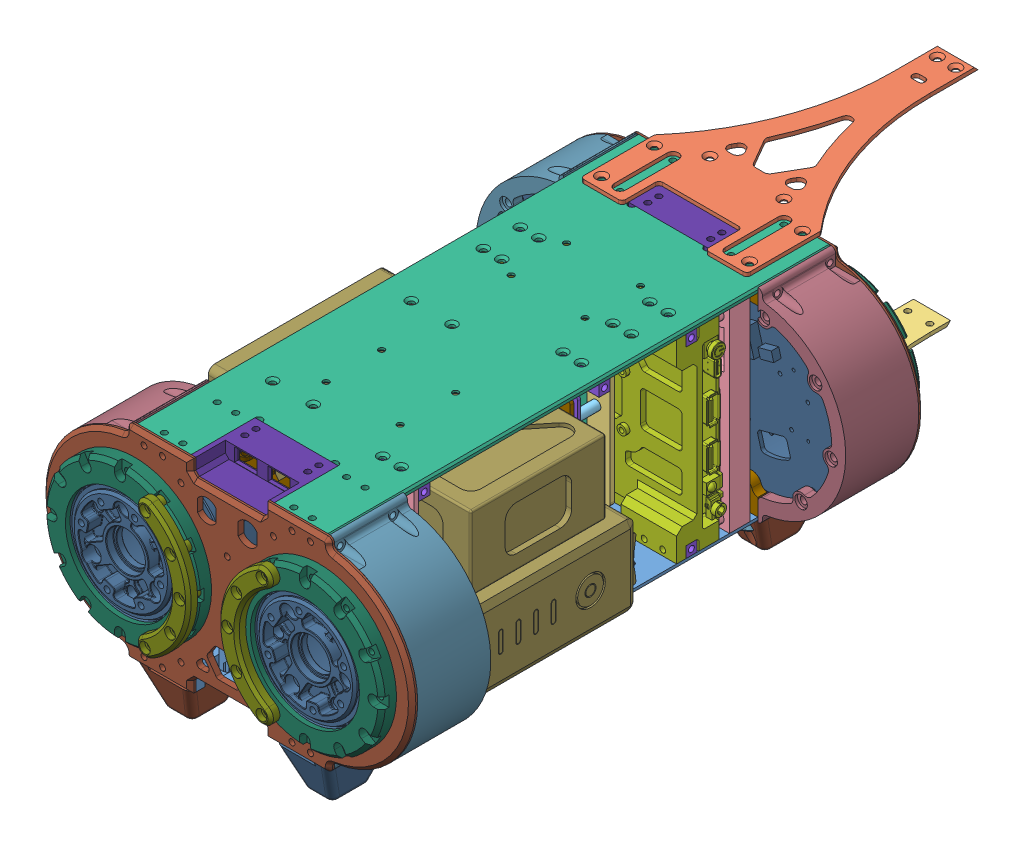
SolidWorks assembly body, configuration 默认. Lengths in mm.
Overall size (225.69 141.84 409).
75 component instances, 29 part files, 207 mates.
Components (placement in the parent):
- 底部碳板-1: 底部碳板 [默认] at (-41.4963 15.0919 267.4422) size (105 2.5 271)
- RoboMaster 电池架-1: RoboMaster 电池架 [默认] at (-3.9963 45.2919 348.8922) x (0 0 -1) z (0 -1 0) size (103.5 37.5 55.4)
- 电池盒碳板1-1: 电池盒碳板1 [默认] at (-41.4963 70.0919 251.3922) x (0 1 0) z (0 0 -1) size (105 105 2.5)
- 电池盒碳板2-1: 电池盒碳板2 [默认] at (-41.4963 70.0919 357.3922) x (0 -1 0) z (0 0 -1) size (105 105 2.5)
- RoboMaster 电池架-2: RoboMaster 电池架 [默认] at (-78.9963 94.8919 348.8922) x (0 0 -1) z (0 1 0) size (103.5 37.5 55.4)
- 线槽-1: 线槽 [默认] at (-81.4963 3.0919 385.6672) x (0 0 -1) z (1 0 0) size (258.44 12 90)
- 顶部碳板-1: 顶部碳板 [默认] at (-41.4963 125.0919 267.4422) x (-1 0 0) z (0 0 1) size (105 2.5 271)
- nuc支架-1: nuc支架 [默认] at (-41.4963 70.0919 204.4422) x (-1 0 0) z (0 0 -1) size (105 105 23)
- 六面螺母_H6_30mm_m3-1: 六面螺母_H6_30mm_m3 [默认] at (-63.9963 17.5919 251.3922) x (0 0 1) z (-1 0 0) size (6 6 30)
- 六面螺母_H6_30mm_m3-2: 六面螺母_H6_30mm_m3 [默认] at (-63.9963 17.5919 348.8922) x (0 0 1) z (-1 0 0) size (6 6 30)
- 六面螺母_H6_30mm_m3-3: 六面螺母_H6_30mm_m3 [默认] at (11.0037 122.5919 251.3922) x (0 -1 0) z (-1 0 0) size (6 6 30)
- 六面螺母_H6_30mm_m3-4: 六面螺母_H6_30mm_m3 [默认] at (11.0037 122.5919 348.8922) x (0 -1 0) z (-1 0 0) size (6 6 30)
- 六面螺母_H6_30mm_m3-5: 六面螺母_H6_30mm_m3 [默认] at (11.0037 122.5919 204.4422) x (0 -1 0) z (-1 0 0) size (6 6 30)
- 六面螺母_H6_30mm_m3-6: 六面螺母_H6_30mm_m3 [默认] at (-93.9963 122.5919 210.4422) x (0 -1 0) z (1 0 0) size (6 6 30)
- 六面螺母_H6_30mm_m3-7: 六面螺母_H6_30mm_m3 [默认] at (-93.9963 23.5919 210.4422) x (0 -1 0) z (1 0 0) size (6 6 30)
- 六面螺母_H6_30mm_m3-8: 六面螺母_H6_30mm_m3 [默认] at (11.0037 23.5919 204.4422) x (0 -1 0) z (-1 0 0) size (6 6 30)
- 髋部碳板2-1: 髋部碳板2 [默认] at (-41.4963 70.0919 166.4922) size (105 105 5)
- 六面螺母_H6_30mm_m3-9: 六面螺母_H6_30mm_m3 [默认] at (11.0037 122.5919 160.4922) x (0 -1 0) z (-1 0 0) size (6 6 30)
- 六面螺母_H6_30mm_m3-10: 六面螺母_H6_30mm_m3 [默认] at (11.0037 23.5919 160.4922) x (0 -1 0) z (-1 0 0) size (6 6 30)
- 六面螺母_H6_30mm_m3-11: 六面螺母_H6_30mm_m3 [默认] at (-93.9963 122.5919 166.4922) x (0 -1 0) z (1 0 0) size (6 6 30)
- 六面螺母_H6_30mm_m3-12: 六面螺母_H6_30mm_m3 [默认] at (-93.9963 23.5919 166.4922) x (0 -1 0) z (1 0 0) size (6 6 30)
- 髋部碳板2-4: 髋部碳板2 [默认] at (-41.4963 70.0919 368.3922) x (-1 0 0) z (0 0 -1) size (105 105 5)
- 六面螺母_H6_30mm_m3-17: 六面螺母_H6_30mm_m3 [默认] at (11.0037 23.5919 368.3922) x (0 -1 0) z (-1 0 0) size (6 6 30)
- 六面螺母_H6_30mm_m3-18: 六面螺母_H6_30mm_m3 [默认] at (11.0037 122.5919 368.3922) x (0 -1 0) z (-1 0 0) size (6 6 30)
- 六面螺母_H6_30mm_m3-19: 六面螺母_H6_30mm_m3 [默认] at (-93.9963 23.5919 374.3922) x (0 -1 0) z (1 0 0) size (6 6 30)
- 六面螺母_H6_30mm_m3-20: 六面螺母_H6_30mm_m3 [默认] at (-93.9963 122.5919 374.3922) x (0 -1 0) z (1 0 0) size (6 6 30)
- Power_unit-1: Power_unit [默认] at (8.5037 70.0919 403.4422) x (0.866025 -0.5 0) z (0 0 1) size (92.01 92.01 49.55)
- Power_unit-2: Power_unit [默认] at (-91.4963 70.0919 403.4422) x (0.5 -0.866025 0) z (0 0 1) size (92.01 92.01 49.55)
- Power_unit-3: Power_unit [默认] at (-91.4963 70.0919 131.4422) x (-0.866025 -0.5 0) z (0 0 -1) size (92.01 92.01 49.55)
- Power_unit-4: Power_unit [默认] at (8.5037 70.0919 131.4422) x (-0.5 -0.866025 0) z (0 0 -1) size (92.01 92.01 49.55)
- 髋部碳板1-1: 髋部碳板1 [默认] at (-41.4963 70.0919 128.9422) size (200 110 3)
- 髋部碳板1-2: 髋部碳板1 [默认] at (-41.4963 70.0919 405.9422) x (-1 0 0) z (0 0 -1) size (200 110 3)
- 六面螺母_H6_30mm_m3-21: 六面螺母_H6_30mm_m3 [默认] at (11.0037 122.5919 396.9422) x (0 -1 0) z (-1 0 0) size (6 6 30)
- 六面螺母_H6_30mm_m3-22: 六面螺母_H6_30mm_m3 [默认] at (11.0037 23.5919 396.9422) x (0 -1 0) z (-1 0 0) size (6 6 30)
- 六面螺母_H6_30mm_m3-23: 六面螺母_H6_30mm_m3 [默认] at (-93.9963 122.5919 402.9422) x (0 -1 0) z (1 0 0) size (6 6 30)
- 六面螺母_H6_30mm_m3-24: 六面螺母_H6_30mm_m3 [默认] at (-93.9963 23.5919 402.9422) x (0 -1 0) z (1 0 0) size (6 6 30)
- 六面螺母_H6_30mm_m3-25: 六面螺母_H6_30mm_m3 [默认] at (-93.9963 23.5919 137.9422) x (0 -1 0) z (1 0 0) size (6 6 30)
- 六面螺母_H6_30mm_m3-26: 六面螺母_H6_30mm_m3 [默认] at (-93.9963 122.5919 137.9422) x (0 -1 0) z (1 0 0) size (6 6 30)
- 六面螺母_H6_30mm_m3-27: 六面螺母_H6_30mm_m3 [默认] at (11.0037 122.5919 131.9422) x (0 -1 0) z (-1 0 0) size (6 6 30)
- 六面螺母_H6_30mm_m3-28: 六面螺母_H6_30mm_m3 [默认] at (11.0037 23.5919 131.9422) x (0 -1 0) z (-1 0 0) size (6 6 30)
- TB47S-1: TB47S [默认] at (28.6537 95.3919 307.8272) x (0 0 1) z (-1 0 0) size (101 43 139)
- TB47S-2: TB47S [默认] at (-111.6463 44.7919 307.8272) x (0 0 1) z (1 0 0) size (101 43 139)
- 髋部盖子-1: 髋部盖子 [默认] at (-91.4963 70.0919 368.3922) x (-1 0 0) z (0 0 -1) size (47.5 110 39.55)
- 髋部盖子_反-1: 髋部盖子_反 [默认] at (13.5037 70.0919 368.3922) x (-1 0 0) z (0 0 -1) size (47.5 110 39.55)
- 髋部盖子_反-2: 髋部盖子_反 [默认] at (-96.4963 70.0919 166.4922) size (47.5 110 39.55)
- 髋部盖子-2: 髋部盖子 [默认] at (8.5037 70.0919 166.4922) size (47.5 110 39.55)
- 轴承压环-1: 轴承压环 [默认] at (8.5037 70.0919 128.9422) x (0 0 -1) z (1 0 0) size (8 83 83)
- 轴承压环-2: 轴承压环 [默认] at (-91.4963 70.0919 128.9422) x (0 0 -1) z (1 0 0) size (8 83 83)
- 轴承压环-3: 轴承压环 [默认] at (8.5037 70.0919 405.9422) x (0 0 1) z (-1 0 0) size (8 83 83)
- 轴承压环-4: 轴承压环 [默认] at (-91.4963 70.0919 405.9422) x (0 0 1) z (-0.866025 -0.5 0) size (8 83 83)
- 限位-1: 限位 [默认] at (8.5037 70.0919 120.9422) x (-1 0 0) z (0 -1 0) size (28.5 9 74.09)
- 限位-2: 限位 [默认] at (-91.4963 70.0919 120.9422) x (1 0 0) z (0 1 0) size (28.5 9 74.09)
- 限位-3: 限位 [默认] at (8.5037 70.0919 413.9422) x (-1 0 0) z (0 1 0) size (28.5 9 74.09)
- 限位-4: 限位 [默认] at (-91.4963 70.0919 413.9422) x (1 0 0) z (0 -1 0) size (28.5 9 74.09)
- xt30分电架-1: xt30分电架 [默认] at (-41.4963 113.0919 166.4922) x (-1 0 0) z (0 0 -1) size (105 19 34.55)
- 分电架盖-1: 分电架盖 [默认] at (-61.4963 116.5919 164.4922) x (1 0 0) z (0 0 -1) size (40 10 17)
- usb&电源出口架-1: usb&电源出口架 [默认] at (-41.4963 27.0919 166.4922) x (1 0 0) z (0 0 -1) size (105 18.85 34.55)
- 颈部-1: 颈部 [默认] at (-41.4963 125.0919 149.9422) size (90 2 160)
- 颈部2-1: 颈部2 [默认] at (-41.4963 15.0919 149.9422) x (-1 0 0) z (0 0 1) size (90 2 145.12)
- nuc盖子-1: nuc盖子 [默认] at (-41.4963 70.0919 190.8422) x (-1 0 0) z (0 0 -1) size (105 105 15)
- 电源控制板垫柱-1: 电源控制板垫柱 [默认] at (3.5037 86.3419 251.3922) size (5 5 14)
- 电源控制板垫柱-2: 电源控制板垫柱 [默认] at (-86.4963 53.8419 251.3922) size (5 5 14)
- 电源控制板垫柱-3: 电源控制板垫柱 [默认] at (-86.4963 33.8419 251.3922) size (5 5 14)
- 电源控制板垫柱-4: 电源控制板垫柱 [默认] at (3.5037 106.3419 251.3922) size (5 5 14)
- 电池盒挡板-1: 电池盒挡板 [默认] at (-41.4963 70.0919 248.8922) x (0 -1 0) z (0 0 -1) size (90.5 98 1)
- nuc工控-1: nuc工控 [默认] at (-41.4954 70.034 192.4422) x (0 -1 0) z (0 0 1) size (101.72 109.81 27.61)
- usb&电源出口架-2: usb&电源出口架 [默认] at (-41.4963 27.0919 368.3922) x (-1 0 0) z (0 0 1) size (105 18.85 34.55)
- 电源管理-1: 电源管理 [默认] at (-41.4963 70.0919 265.3922) size (114.55 100.97 17.7)
- 电源管理挡板-1: 电源管理挡板 [默认] at (-41.4963 70.0919 266.9923) size (100.97 100.97 4)
- xt30分电架-2: xt30分电架 [默认] at (-41.4963 113.0919 368.3922) size (105 19 34.55)
- 分电架盖-2: 分电架盖 [默认] at (-21.4963 116.5919 370.3922) x (-1 0 0) z (0 0 1) size (40 10 17)
- 脚垫-1: 脚垫 [默认] at (-93.9963 15.0919 130.9422) x (1 0 0) z (0 0 -1) size (29.33 24 39)
- 脚垫-2: 脚垫 [默认] at (11.0037 15.0919 403.9422) x (-1 0 0) z (0 0 1) size (29.33 24 39)
- 脚垫_镜像-1: 脚垫_镜像 [默认] at (10.8002 15.0919 130.9422) x (-1 0 0) z (0 0 -1) size (29.33 24 39)
- 脚垫_镜像-2: 脚垫_镜像 [默认] at (-93.9963 15.0919 403.9422) size (29.33 24 39)
Mates (geometry in assembly coordinates):
- 同心1: concentric anti-aligned: cylinder of 底部碳板-1 through (-6.4963 7.5919 346.3922) axis (0 1 0) radius 1.6; cylinder of RoboMaster 电池架-1 through (-6.4963 17.5919 346.3922) axis (0 -1 0) radius 1.25
- 同心2: concentric anti-aligned: cylinder of 底部碳板-1 through (-28.4963 7.5919 346.3922) axis (0 1 0) radius 1.6; cylinder of RoboMaster 电池架-1 through (-28.4963 17.5919 346.3922) axis (0 -1 0) radius 1.25
- 重合1: coincident anti-aligned: plane of 底部碳板-1 through (-41.4963 17.5919 267.4422) normal (0 1 0); plane of RoboMaster 电池架-1 through (-30.9964 17.5919 260.6928) normal (0 -1 0)
- 重合2: coincident anti-aligned: plane of RoboMaster 电池架-1 through (-17.4963 45.2919 354.8922) normal (0 0 1); plane of 电池盒碳板2-1 through (-41.4963 70.0919 354.8922) normal (0 0 -1)
- 同心3: concentric anti-aligned: cylinder of RoboMaster 电池架-1 through (-28.4963 67.7919 348.8922) axis (0 0 1) radius 1.25; cylinder of 电池盒碳板2-1 through (-28.4963 67.7919 364.8922) axis (0 0 -1) radius 1.6
- 同心4: concentric anti-aligned: cylinder of RoboMaster 电池架-1 through (-9.9963 67.7919 348.8922) axis (0 0 1) radius 1.25; cylinder of 电池盒碳板2-1 through (-9.9963 67.7919 364.8922) axis (0 0 -1) radius 1.6
- 同心5: concentric anti-aligned: cylinder of 电池盒碳板2-1 through (-72.9963 72.3919 364.8922) axis (0 0 -1) radius 1.6; cylinder of RoboMaster 电池架-2 through (-72.9963 72.3919 348.8922) axis (0 0 1) radius 1.25
- 同心6: concentric anti-aligned: cylinder of 电池盒碳板2-1 through (-54.4963 72.3919 364.8922) axis (0 0 -1) radius 1.6; cylinder of RoboMaster 电池架-2 through (-54.4963 72.3919 348.8922) axis (0 0 1) radius 1.25
- 重合3: coincident anti-aligned: plane of RoboMaster 电池架-1 through (-51.4793 67.0419 251.3922) normal (0 0 -1); plane of 电池盒碳板1-1 through (-41.4963 70.0919 251.3922) normal (0 0 1)
- 同心7: concentric aligned: cylinder of RoboMaster 电池架-1 through (-6.4963 67.7919 261.3922) axis (0 0 -1) radius 1.25; cylinder of 电池盒碳板1-1 through (-6.4963 67.7919 258.8922) axis (0 0 -1) radius 1.6
- 同心8: concentric aligned: cylinder of RoboMaster 电池架-1 through (-28.4963 67.7919 257.3922) axis (0 0 -1) radius 1.25; cylinder of 电池盒碳板1-1 through (-28.4963 67.7919 258.8922) axis (0 0 -1) radius 1.6
- 同心10: concentric anti-aligned: cylinder of 底部碳板-1 through (-81.4963 7.5919 163.4922) axis (0 1 0) radius 1.6; cylinder of 线槽-1 through (-81.4963 15.0919 163.4922) axis (0 -1 0) radius 1.65
- 同心11: concentric anti-aligned: cylinder of 底部碳板-1 through (-1.4963 7.5919 163.4922) axis (0 1 0) radius 1.6; cylinder of 线槽-1 through (-1.4963 15.0919 163.4922) axis (0 -1 0) radius 1.65
- 重合5: coincident anti-aligned: plane of 底部碳板-1 through (-41.4963 15.0919 267.4422) normal (0 -1 0); plane of 线槽-1 through (-81.4963 15.0919 385.6672) normal (0 1 0)
- 重合6: coincident anti-aligned: plane of 电池盒碳板2-1 through (-93.9963 122.5919 354.8922) normal (0 1 0); plane of 顶部碳板-1 through (-41.4963 122.5919 267.4422) normal (0 -1 0)
- 同心12: concentric anti-aligned: cylinder of RoboMaster 电池架-2 through (-54.4963 122.5919 346.3922) axis (0 1 0) radius 1.25; cylinder of 顶部碳板-1 through (-54.4963 132.5919 346.3922) axis (0 -1 0) radius 1.6
- 同心13: concentric anti-aligned: cylinder of RoboMaster 电池架-2 through (-76.4963 122.5919 346.3922) axis (0 1 0) radius 1.25; cylinder of 顶部碳板-1 through (-76.4963 132.5919 346.3922) axis (0 -1 0) radius 1.6
- 同心14: concentric anti-aligned: cylinder of 电池盒碳板1-1 through (-86.4963 20.5919 258.8922) axis (0 0 -1) radius 1.6; cylinder of 六面螺母_H6_30mm_m3-1 through (-86.4963 20.5919 250.3922) axis (0 0 1) radius 1.6
- 同心15: concentric anti-aligned: cylinder of 电池盒碳板1-1 through (-76.4963 20.5919 258.8922) axis (0 0 -1) radius 1.6; cylinder of 六面螺母_H6_30mm_m3-1 through (-76.4963 20.5919 250.3922) axis (0 0 1) radius 1.6
- 同心16: concentric aligned: cylinder of 底部碳板-1 through (-81.4963 7.5919 254.3922) axis (0 1 0) radius 1.6; cylinder of 六面螺母_H6_30mm_m3-1 through (-81.4963 16.5919 254.3922) axis (0 1 0) radius 1.6
- 同心17: concentric anti-aligned: cylinder of 电池盒碳板2-1 through (-86.4963 20.5919 364.8922) axis (0 0 -1) radius 1.6; cylinder of 六面螺母_H6_30mm_m3-2 through (-86.4963 20.5919 347.8922) axis (0 0 1) radius 1.6
- 同心18: concentric anti-aligned: cylinder of 电池盒碳板2-1 through (-76.4963 20.5919 364.8922) axis (0 0 -1) radius 1.6; cylinder of 六面螺母_H6_30mm_m3-2 through (-76.4963 20.5919 347.8922) axis (0 0 1) radius 1.6
- 同心19: concentric aligned: cylinder of 底部碳板-1 through (-81.4963 7.5919 351.8922) axis (0 1 0) radius 1.6; cylinder of 六面螺母_H6_30mm_m3-2 through (-81.4963 16.5919 351.8922) axis (0 1 0) radius 1.6
- 同心20: concentric anti-aligned: cylinder of 电池盒碳板2-1 through (-6.4963 119.5919 364.8922) axis (0 0 -1) radius 1.6; cylinder of 六面螺母_H6_30mm_m3-4 through (-6.4963 119.5919 347.8922) axis (0 0 1) radius 1.6
- 同心21: concentric anti-aligned: cylinder of 电池盒碳板2-1 through (3.5037 119.5919 364.8922) axis (0 0 -1) radius 1.6; cylinder of 六面螺母_H6_30mm_m3-4 through (3.5037 119.5919 347.8922) axis (0 0 1) radius 1.6
- 同心22: concentric anti-aligned: cylinder of 顶部碳板-1 through (-1.4963 115.0919 351.8922) axis (0 1 0) radius 1.6; cylinder of 六面螺母_H6_30mm_m3-4 through (-1.4963 123.5919 351.8922) axis (0 -1 0) radius 1.6
- 重合7: coincident anti-aligned: plane of 电池盒碳板2-1 through (-41.4963 70.0919 354.8922) normal (0 0 -1); plane of 六面螺母_H6_30mm_m3-4 through (-18.9963 116.5919 354.8922) normal (0 0 1)
- 同心23: concentric anti-aligned: cylinder of 电池盒碳板1-1 through (3.5037 119.5919 258.8922) axis (0 0 -1) radius 1.6; cylinder of 六面螺母_H6_30mm_m3-3 through (3.5037 119.5919 250.3922) axis (0 0 1) radius 1.6
- 重合8: coincident anti-aligned: plane of 电池盒碳板1-1 through (-41.4963 70.0919 251.3922) normal (0 0 1); plane of 六面螺母_H6_30mm_m3-3 through (-18.9963 122.5919 251.3922) normal (0 0 -1)
- 重合9: coincident anti-aligned: plane of 顶部碳板-1 through (-41.4963 122.5919 267.4422) normal (0 -1 0); plane of 六面螺母_H6_30mm_m3-5 through (-18.9963 122.5919 210.4422) normal (0 1 0)
- 重合10: coincident anti-aligned: plane of 顶部碳板-1 through (-41.4963 122.5919 267.4422) normal (0 -1 0); plane of 六面螺母_H6_30mm_m3-6 through (-63.9963 122.5919 204.4422) normal (0 1 0)
- 同心28: concentric aligned: cylinder of 顶部碳板-1 through (-81.4963 132.5919 207.4422) axis (0 -1 0) radius 1.6; cylinder of 六面螺母_H6_30mm_m3-6 through (-81.4963 123.5919 207.4422) axis (0 -1 0) radius 1.6
- 同心29: concentric aligned: cylinder of 顶部碳板-1 through (-71.4963 132.5919 207.4422) axis (0 -1 0) radius 1.6; cylinder of 六面螺母_H6_30mm_m3-6 through (-71.4963 123.5919 207.4422) axis (0 -1 0) radius 1.6
- 同心30: concentric aligned: cylinder of 顶部碳板-1 through (-1.4963 132.5919 207.4422) axis (0 -1 0) radius 1.6; cylinder of 六面螺母_H6_30mm_m3-5 through (-1.4963 123.5919 207.4422) axis (0 -1 0) radius 1.6
- 同心31: concentric aligned: cylinder of 顶部碳板-1 through (-11.4963 132.5919 207.4422) axis (0 -1 0) radius 1.6; cylinder of 六面螺母_H6_30mm_m3-5 through (-11.4963 123.5919 207.4422) axis (0 -1 0) radius 1.6
- 同心32: concentric anti-aligned: cylinder of 底部碳板-1 through (-81.4963 7.5919 207.4422) axis (0 1 0) radius 1.6; cylinder of 六面螺母_H6_30mm_m3-7 through (-81.4963 24.5919 207.4422) axis (0 -1 0) radius 1.6
- 同心33: concentric anti-aligned: cylinder of 底部碳板-1 through (-1.4963 7.5919 207.4422) axis (0 1 0) radius 1.6; cylinder of 六面螺母_H6_30mm_m3-8 through (-1.4963 24.5919 207.4422) axis (0 -1 0) radius 1.6
- 同心34: concentric anti-aligned: cylinder of 底部碳板-1 through (-11.4963 7.5919 207.4422) axis (0 1 0) radius 1.6; cylinder of 六面螺母_H6_30mm_m3-8 through (-11.4963 24.5919 207.4422) axis (0 -1 0) radius 1.6
- 同心35: concentric anti-aligned: cylinder of 底部碳板-1 through (-71.4963 7.5919 207.4422) axis (0 1 0) radius 1.6; cylinder of 六面螺母_H6_30mm_m3-7 through (-71.4963 24.5919 207.4422) axis (0 -1 0) radius 1.6
- 重合11: coincident anti-aligned: plane of 底部碳板-1 through (-41.4963 17.5919 267.4422) normal (0 1 0); plane of 六面螺母_H6_30mm_m3-8 through (-18.9963 17.5919 204.4422) normal (0 -1 0)
- 重合12: coincident anti-aligned: plane of 底部碳板-1 through (-41.4963 17.5919 267.4422) normal (0 1 0); plane of 六面螺母_H6_30mm_m3-7 through (-63.9963 17.5919 210.4422) normal (0 -1 0)
- 同心36: concentric anti-aligned: cylinder of nuc支架-1 through (-86.4963 119.5919 210.4422) axis (0 0 1) radius 1.6; cylinder of 六面螺母_H6_30mm_m3-6 through (-86.4963 119.5919 211.4422) axis (0 0 -1) radius 1.6
- 重合13: coincident anti-aligned: plane of nuc支架-1 through (-41.4963 70.0919 210.4422) normal (0 0 -1); plane of 六面螺母_H6_30mm_m3-6 through (-63.9963 122.5919 210.4422) normal (0 0 1)
- 同心37: concentric aligned: cylinder of nuc支架-1 through (3.5037 119.5919 210.4422) axis (0 0 1) radius 1.6; cylinder of 六面螺母_H6_30mm_m3-5 through (3.5037 119.5919 203.4422) axis (0 0 1) radius 1.6
- 同心38: concentric aligned: cylinder of 髋部碳板2-1 through (3.5037 119.5919 161.4922) axis (0 0 1) radius 1.6; cylinder of 六面螺母_H6_30mm_m3-9 through (3.5037 119.5919 159.4922) axis (0 0 1) radius 1.6
- 同心39: concentric aligned: cylinder of 髋部碳板2-1 through (3.5037 20.5919 161.4922) axis (0 0 1) radius 1.6; cylinder of 六面螺母_H6_30mm_m3-10 through (3.5037 20.5919 159.4922) axis (0 0 1) radius 1.6
- 重合15: coincident anti-aligned: plane of 髋部碳板2-1 through (-91.4963 70.0919 166.4922) normal (0 0 -1); plane of 六面螺母_H6_30mm_m3-10 through (-18.9963 17.5919 166.4922) normal (0 0 1)
- 重合16: coincident anti-aligned: plane of 髋部碳板2-1 through (-91.4963 70.0919 166.4922) normal (0 0 -1); plane of 六面螺母_H6_30mm_m3-9 through (-18.9963 116.5919 166.4922) normal (0 0 1)
- 同心40: concentric anti-aligned: cylinder of 髋部碳板2-1 through (-86.4963 119.5919 161.4922) axis (0 0 1) radius 1.6; cylinder of 六面螺母_H6_30mm_m3-11 through (-86.4963 119.5919 167.4922) axis (0 0 -1) radius 1.6
- 同心41: concentric anti-aligned: cylinder of 髋部碳板2-1 through (-86.4963 20.5919 161.4922) axis (0 0 1) radius 1.6; cylinder of 六面螺母_H6_30mm_m3-12 through (-86.4963 20.5919 167.4922) axis (0 0 -1) radius 1.6
- 重合17: coincident anti-aligned: plane of 髋部碳板2-1 through (-91.4963 70.0919 166.4922) normal (0 0 -1); plane of 六面螺母_H6_30mm_m3-12 through (-63.9963 23.5919 166.4922) normal (0 0 1)
- 重合18: coincident anti-aligned: plane of 髋部碳板2-1 through (-91.4963 70.0919 166.4922) normal (0 0 -1); plane of 六面螺母_H6_30mm_m3-11 through (-63.9963 122.5919 166.4922) normal (0 0 1)
- 同心42: concentric anti-aligned: cylinder of 底部碳板-1 through (-71.4963 7.5919 163.4922) axis (0 1 0) radius 1.6; cylinder of 六面螺母_H6_30mm_m3-12 through (-71.4963 24.5919 163.4922) axis (0 -1 0) radius 1.6
- 同心43: concentric anti-aligned: cylinder of 底部碳板-1 through (-11.4963 7.5919 163.4922) axis (0 1 0) radius 1.6; cylinder of 六面螺母_H6_30mm_m3-10 through (-11.4963 24.5919 163.4922) axis (0 -1 0) radius 1.6
- 重合19: coincident anti-aligned: plane of 底部碳板-1 through (-41.4963 17.5919 267.4422) normal (0 1 0); plane of 六面螺母_H6_30mm_m3-10 through (-18.9963 17.5919 160.4922) normal (0 -1 0)
- 同心48: concentric aligned: cylinder of 髋部碳板2-4 through (-86.4963 119.5919 373.3922) axis (0 0 -1) radius 1.6; cylinder of 六面螺母_H6_30mm_m3-20 through (-86.4963 119.5919 375.3922) axis (0 0 -1) radius 1.6
- 同心49: concentric aligned: cylinder of 髋部碳板2-4 through (-86.4963 20.5919 373.3922) axis (0 0 -1) radius 1.6; cylinder of 六面螺母_H6_30mm_m3-19 through (-86.4963 20.5919 375.3922) axis (0 0 -1) radius 1.6
- 重合24: coincident anti-aligned: plane of 髋部碳板2-4 through (8.5037 70.0919 368.3922) normal (0 0 1); plane of 六面螺母_H6_30mm_m3-19 through (-63.9963 17.5919 368.3922) normal (0 0 -1)
- 重合25: coincident anti-aligned: plane of 髋部碳板2-4 through (8.5037 70.0919 368.3922) normal (0 0 1); plane of 六面螺母_H6_30mm_m3-20 through (-63.9963 116.5919 368.3922) normal (0 0 -1)
- 同心50: concentric anti-aligned: cylinder of 髋部碳板2-4 through (3.5037 119.5919 373.3922) axis (0 0 -1) radius 1.6; cylinder of 六面螺母_H6_30mm_m3-18 through (3.5037 119.5919 367.3922) axis (0 0 1) radius 1.6
- 同心51: concentric anti-aligned: cylinder of 髋部碳板2-4 through (3.5037 20.5919 373.3922) axis (0 0 -1) radius 1.6; cylinder of 六面螺母_H6_30mm_m3-17 through (3.5037 20.5919 367.3922) axis (0 0 1) radius 1.6
- 重合26: coincident anti-aligned: plane of 髋部碳板2-4 through (8.5037 70.0919 368.3922) normal (0 0 1); plane of 六面螺母_H6_30mm_m3-17 through (-18.9963 23.5919 368.3922) normal (0 0 -1)
- 重合27: coincident anti-aligned: plane of 髋部碳板2-4 through (8.5037 70.0919 368.3922) normal (0 0 1); plane of 六面螺母_H6_30mm_m3-18 through (-18.9963 122.5919 368.3922) normal (0 0 -1)
- 重合30: coincident anti-aligned: plane of 顶部碳板-1 through (-41.4963 122.5919 267.4422) normal (0 -1 0); plane of 髋部碳板2-4 through (11.0037 122.5919 373.3922) normal (0 1 0)
- 同心58: concentric anti-aligned: cylinder of 顶部碳板-1 through (-81.4963 115.0919 371.3922) axis (0 1 0) radius 1.6; cylinder of 六面螺母_H6_30mm_m3-20 through (-81.4963 123.5919 371.3922) axis (0 -1 0) radius 1.6
- 同心59: concentric anti-aligned: cylinder of 顶部碳板-1 through (-1.4963 115.0919 371.3922) axis (0 1 0) radius 1.6; cylinder of 六面螺母_H6_30mm_m3-18 through (-1.4963 123.5919 371.3922) axis (0 -1 0) radius 1.6
- 同心60: concentric anti-aligned: cylinder of 底部碳板-1 through (-11.4963 7.5919 371.3922) axis (0 1 0) radius 1.6; cylinder of 六面螺母_H6_30mm_m3-17 through (-11.4963 24.5919 371.3922) axis (0 -1 0) radius 1.6
- 同心61: concentric anti-aligned: cylinder of 底部碳板-1 through (-71.4963 7.5919 371.3922) axis (0 1 0) radius 1.6; cylinder of 六面螺母_H6_30mm_m3-19 through (-71.4963 24.5919 371.3922) axis (0 -1 0) radius 1.6
- 同心62: concentric aligned: cylinder of 髋部碳板2-1 through (-65.6239 103.8094 171.4922) axis (0 0 -1) radius 1.85; cylinder of Power_unit-3 through (-65.6239 103.8094 161.9922) axis (0 0 -1) radius 1.45
- 重合31: coincident anti-aligned: plane of 髋部碳板2-1 through (-91.4963 70.0919 166.4922) normal (0 0 -1); plane of Power_unit-3 through (-91.4963 70.0919 166.4922) normal (0 0 1)
- 同心63: concentric aligned: cylinder of 髋部碳板2-1 through (-49.3599 75.6392 171.4922) axis (0 0 -1) radius 1.85; cylinder of Power_unit-3 through (-49.3599 75.6392 161.9922) axis (0 0 -1) radius 1.45
- 重合32: coincident anti-aligned: plane of 髋部碳板2-1 through (-91.4963 70.0919 166.4922) normal (0 0 -1); plane of Power_unit-4 through (8.5037 70.0919 166.4922) normal (0 0 1)
- 同心64: concentric aligned: cylinder of 髋部碳板2-1 through (-17.3687 103.8094 171.4922) axis (0 0 -1) radius 1.85; cylinder of Power_unit-4 through (-17.3687 103.8094 161.9922) axis (0 0 -1) radius 1.45
- 同心65: concentric aligned: cylinder of 髋部碳板2-1 through (-33.6327 75.6392 171.4922) axis (0 0 -1) radius 1.85; cylinder of Power_unit-4 through (-33.6327 75.6392 161.9922) axis (0 0 -1) radius 1.45
- 同心66: concentric aligned: cylinder of 髋部碳板2-4 through (-65.6239 103.8094 363.3922) axis (0 0 1) radius 1.85; cylinder of Power_unit-2 through (-65.6239 103.8094 372.8922) axis (0 0 1) radius 1.45
- 同心67: concentric aligned: cylinder of 髋部碳板2-4 through (-49.3599 75.6392 363.3922) axis (0 0 1) radius 1.85; cylinder of Power_unit-2 through (-49.3599 75.6392 372.8922) axis (0 0 1) radius 1.45
- 重合33: coincident anti-aligned: plane of 髋部碳板2-4 through (8.5037 70.0919 368.3922) normal (0 0 1); plane of Power_unit-2 through (-91.4963 70.0919 368.3922) normal (0 0 -1)
- 重合34: coincident anti-aligned: plane of 髋部碳板2-4 through (8.5037 70.0919 368.3922) normal (0 0 1); plane of Power_unit-1 through (8.5037 70.0919 368.3922) normal (0 0 -1)
- 同心68: concentric aligned: cylinder of 髋部碳板2-4 through (-17.3687 103.8094 363.3922) axis (0 0 1) radius 1.85; cylinder of Power_unit-1 through (-17.3687 103.8094 372.8922) axis (0 0 1) radius 1.45
- 同心69: concentric aligned: cylinder of 髋部碳板2-4 through (-33.6327 75.6392 363.3922) axis (0 0 1) radius 1.85; cylinder of Power_unit-1 through (-33.6327 75.6392 372.8922) axis (0 0 1) radius 1.45
- 重合35: coincident anti-aligned: plane of Power_unit-1 through (8.5037 70.0919 402.9422) normal (0 0 1); plane of 髋部碳板1-2 through (-91.4963 70.0919 402.9422) normal (0 0 -1)
- 同心70: concentric aligned: cylinder of Power_unit-2 through (-54.4963 70.0919 402.9422) axis (0 0 1) radius 1.25; cylinder of 髋部碳板1-2 through (-54.4963 70.0919 402.9422) axis (0 0 1) radius 1.6
- 同心71: concentric aligned: cylinder of Power_unit-1 through (-28.4963 70.0919 402.9422) axis (0 0 1) radius 1.25; cylinder of 髋部碳板1-2 through (-28.4963 70.0919 402.9422) axis (0 0 1) radius 1.6
- 重合36: coincident anti-aligned: plane of Power_unit-3 through (-91.4963 70.0919 131.9422) normal (0 0 -1); plane of 髋部碳板1-1 through (8.5037 70.0919 131.9422) normal (0 0 1)
- 同心72: concentric aligned: cylinder of Power_unit-3 through (-54.4963 70.0919 131.9422) axis (0 0 -1) radius 1.25; cylinder of 髋部碳板1-1 through (-54.4963 70.0919 131.9422) axis (0 0 -1) radius 1.6
- 同心73: concentric aligned: cylinder of Power_unit-4 through (-28.4963 70.0919 131.9422) axis (0 0 -1) radius 1.25; cylinder of 髋部碳板1-1 through (-28.4963 70.0919 131.9422) axis (0 0 -1) radius 1.6
- 同心74: concentric anti-aligned: cylinder of 顶部碳板-1 through (-1.4963 115.0919 399.9422) axis (0 1 0) radius 1.6; cylinder of 六面螺母_H6_30mm_m3-21 through (-1.4963 123.5919 399.9422) axis (0 -1 0) radius 1.6
- 同心75: concentric anti-aligned: cylinder of 顶部碳板-1 through (-11.4963 115.0919 399.9422) axis (0 1 0) radius 1.6; cylinder of 六面螺母_H6_30mm_m3-21 through (-11.4963 123.5919 399.9422) axis (0 -1 0) radius 1.6
- 重合37: coincident anti-aligned: plane of 顶部碳板-1 through (-41.4963 122.5919 267.4422) normal (0 -1 0); plane of 六面螺母_H6_30mm_m3-21 through (-18.9963 122.5919 402.9422) normal (0 1 0)
- 同心76: concentric anti-aligned: cylinder of 底部碳板-1 through (-1.4963 7.5919 399.9422) axis (0 1 0) radius 1.6; cylinder of 六面螺母_H6_30mm_m3-22 through (-1.4963 24.5919 399.9422) axis (0 -1 0) radius 1.6
- 同心77: concentric anti-aligned: cylinder of 底部碳板-1 through (-11.4963 7.5919 399.9422) axis (0 1 0) radius 1.6; cylinder of 六面螺母_H6_30mm_m3-22 through (-11.4963 24.5919 399.9422) axis (0 -1 0) radius 1.6
- 重合38: coincident anti-aligned: plane of 底部碳板-1 through (-41.4963 17.5919 267.4422) normal (0 1 0); plane of 六面螺母_H6_30mm_m3-22 through (-18.9963 17.5919 396.9422) normal (0 -1 0)
- 重合39: coincident anti-aligned: plane of 髋部碳板1-2 through (-91.4963 70.0919 402.9422) normal (0 0 -1); plane of 六面螺母_H6_30mm_m3-23 through (-63.9963 122.5919 402.9422) normal (0 0 1)
- 同心78: concentric anti-aligned: cylinder of 髋部碳板1-2 through (-86.4963 119.5919 395.9422) axis (0 0 1) radius 1.6; cylinder of 六面螺母_H6_30mm_m3-23 through (-86.4963 119.5919 403.9422) axis (0 0 -1) radius 1.6
- 同心79: concentric anti-aligned: cylinder of 髋部碳板1-2 through (-76.4963 119.5919 395.9422) axis (0 0 1) radius 1.6; cylinder of 六面螺母_H6_30mm_m3-23 through (-76.4963 119.5919 403.9422) axis (0 0 -1) radius 1.6
- 同心80: concentric anti-aligned: cylinder of 髋部碳板1-2 through (-86.4963 20.5919 395.9422) axis (0 0 1) radius 1.6; cylinder of 六面螺母_H6_30mm_m3-24 through (-86.4963 20.5919 403.9422) axis (0 0 -1) radius 1.6
- 同心81: concentric anti-aligned: cylinder of 髋部碳板1-2 through (-76.4963 20.5919 395.9422) axis (0 0 1) radius 1.6; cylinder of 六面螺母_H6_30mm_m3-24 through (-76.4963 20.5919 403.9422) axis (0 0 -1) radius 1.6
- 重合40: coincident anti-aligned: plane of 髋部碳板1-2 through (-91.4963 70.0919 402.9422) normal (0 0 -1); plane of 六面螺母_H6_30mm_m3-24 through (-63.9963 23.5919 402.9422) normal (0 0 1)
- 同心82: concentric aligned: cylinder of 髋部碳板1-1 through (-76.4963 119.5919 138.9422) axis (0 0 -1) radius 1.6; cylinder of 六面螺母_H6_30mm_m3-26 through (-76.4963 119.5919 138.9422) axis (0 0 -1) radius 1.6
- 同心83: concentric aligned: cylinder of 髋部碳板1-1 through (-86.4963 119.5919 138.9422) axis (0 0 -1) radius 1.6; cylinder of 六面螺母_H6_30mm_m3-26 through (-86.4963 119.5919 138.9422) axis (0 0 -1) radius 1.6
- 重合41: coincident anti-aligned: plane of 髋部碳板1-1 through (8.5037 70.0919 131.9422) normal (0 0 1); plane of 六面螺母_H6_30mm_m3-26 through (-63.9963 116.5919 131.9422) normal (0 0 -1)
- 同心84: concentric aligned: cylinder of 髋部碳板1-1 through (-86.4963 20.5919 138.9422) axis (0 0 -1) radius 1.6; cylinder of 六面螺母_H6_30mm_m3-25 through (-86.4963 20.5919 138.9422) axis (0 0 -1) radius 1.6
- 同心85: concentric aligned: cylinder of 髋部碳板1-1 through (-76.4963 20.5919 138.9422) axis (0 0 -1) radius 1.6; cylinder of 六面螺母_H6_30mm_m3-25 through (-76.4963 20.5919 138.9422) axis (0 0 -1) radius 1.6
- 重合42: coincident anti-aligned: plane of 髋部碳板1-1 through (8.5037 70.0919 131.9422) normal (0 0 1); plane of 六面螺母_H6_30mm_m3-25 through (-63.9963 17.5919 131.9422) normal (0 0 -1)
- 同心86: concentric anti-aligned: cylinder of 髋部碳板1-1 through (3.5037 119.5919 138.9422) axis (0 0 -1) radius 1.6; cylinder of 六面螺母_H6_30mm_m3-27 through (3.5037 119.5919 130.9422) axis (0 0 1) radius 1.6
- 同心87: concentric anti-aligned: cylinder of 髋部碳板1-1 through (-6.4963 119.5919 138.9422) axis (0 0 -1) radius 1.6; cylinder of 六面螺母_H6_30mm_m3-27 through (-6.4963 119.5919 130.9422) axis (0 0 1) radius 1.6
- 重合43: coincident anti-aligned: plane of 髋部碳板1-1 through (8.5037 70.0919 131.9422) normal (0 0 1); plane of 六面螺母_H6_30mm_m3-27 through (-18.9963 122.5919 131.9422) normal (0 0 -1)
- 同心88: concentric anti-aligned: cylinder of 底部碳板-1 through (-1.4963 7.5919 134.9422) axis (0 1 0) radius 1.6; cylinder of 六面螺母_H6_30mm_m3-28 through (-1.4963 24.5919 134.9422) axis (0 -1 0) radius 1.6
- 重合44: coincident anti-aligned: plane of 底部碳板-1 through (-41.4963 17.5919 267.4422) normal (0 1 0); plane of 六面螺母_H6_30mm_m3-28 through (-18.9963 17.5919 131.9422) normal (0 -1 0)
- 同心89: concentric anti-aligned: cylinder of 底部碳板-1 through (-11.4963 7.5919 134.9422) axis (0 1 0) radius 1.6; cylinder of 六面螺母_H6_30mm_m3-28 through (-11.4963 24.5919 134.9422) axis (0 -1 0) radius 1.6
- 重合45: coincident anti-aligned: plane of RoboMaster 电池架-2 through (-73.3463 100.8419 264.1922) normal (-1 0 0); plane of TB47S-1 through (-73.3463 95.3919 307.8272) normal (1 0 0)
- 重合48: coincident anti-aligned: plane of RoboMaster 电池架-2 through (-82.9463 101.7419 266.8272) normal (0 0 1); plane of TB47S-1 through (-76.3463 109.8919 266.8272) normal (0 0 -1)
- 重合49: coincident anti-aligned: plane of RoboMaster 电池架-2 through (-49.2951 115.3919 252.391) normal (0 -1 0); plane of TB47S-1 through (-80.3463 115.3919 250.8022) normal (0 1 0)
- 重合51: coincident anti-aligned: plane of RoboMaster 电池架-1 through (-33.6975 24.7919 252.391) normal (0 1 0); plane of TB47S-2 through (-2.6463 24.7919 250.8022) normal (0 -1 0)
- 重合52: coincident anti-aligned: plane of RoboMaster 电池架-1 through (-0.0463 49.4419 266.8272) normal (0 0 1); plane of TB47S-2 through (-6.6463 43.2919 266.8272) normal (0 0 -1)
- 重合53: coincident anti-aligned: plane of RoboMaster 电池架-1 through (-9.6463 39.3419 264.1922) normal (1 0 0); plane of TB47S-2 through (-9.6463 44.7919 307.8272) normal (-1 0 0)
- 重合54: coincident anti-aligned: plane of 六面螺母_H6_30mm_m3-21 through (11.0037 122.5919 396.9422) normal (1 0 0); plane of 髋部盖子_反-1 through (11.0037 20.0919 404.3922) normal (-1 0 0)
- 同心90: concentric anti-aligned: cylinder of Power_unit-1 through (34.3761 36.3744 372.8922) axis (0 0 1) radius 1.45; cylinder of 髋部盖子_反-1 through (34.3761 36.3744 373.3922) axis (0 0 -1) radius 1.9
- 同心91: concentric anti-aligned: cylinder of Power_unit-1 through (42.2212 95.9642 372.8922) axis (0 0 1) radius 1.45; cylinder of 髋部盖子_反-1 through (42.2212 95.9642 373.3922) axis (0 0 -1) radius 1.9
- 重合55: coincident anti-aligned: plane of 髋部碳板1-2 through (-91.4963 70.0919 402.9422) normal (0 0 -1); plane of 髋部盖子_反-1 through (13.5037 70.0919 402.9422) normal (0 0 1)
- 重合56: coincident anti-aligned: plane of Power_unit-2 through (-91.4963 70.0919 368.3922) normal (0 0 -1); plane of 髋部盖子-1 through (-91.4963 70.0919 368.3922) normal (0 0 1)
- 同心92: concentric anti-aligned: cylinder of Power_unit-2 through (-97.0437 112.2283 372.8922) axis (0 0 1) radius 1.45; cylinder of 髋部盖子-1 through (-97.0437 112.2283 373.3922) axis (0 0 -1) radius 1.9
- 同心93: concentric anti-aligned: cylinder of Power_unit-2 through (-133.6327 64.5445 372.8922) axis (0 0 1) radius 1.45; cylinder of 髋部盖子-1 through (-133.6327 64.5445 373.3922) axis (0 0 -1) radius 1.9
- 重合57: coincident anti-aligned: plane of Power_unit-4 through (8.5037 70.0919 166.4922) normal (0 0 1); plane of 髋部盖子-2 through (8.5037 70.0919 166.4922) normal (0 0 -1)
- 同心94: concentric anti-aligned: cylinder of Power_unit-4 through (14.0511 112.2283 161.9922) axis (0 0 -1) radius 1.45; cylinder of 髋部盖子-2 through (14.0511 112.2283 161.4922) axis (0 0 1) radius 1.9
- 重合58: coincident anti-aligned: plane of 髋部碳板2-1 through (11.0037 17.5919 161.4922) normal (1 0 0); plane of 髋部盖子-2 through (11.0037 20.0919 130.4922) normal (-1 0 0)
- 重合59: coincident anti-aligned: plane of Power_unit-3 through (-91.4963 70.0919 166.4922) normal (0 0 1); plane of 髋部盖子_反-2 through (-96.4963 70.0919 166.4922) normal (0 0 -1)
- 同心95: concentric anti-aligned: cylinder of Power_unit-3 through (-97.0437 112.2283 161.9922) axis (0 0 -1) radius 1.45; cylinder of 髋部盖子_反-2 through (-97.0437 112.2283 161.4922) axis (0 0 1) radius 1.9
- 同心96: concentric anti-aligned: cylinder of Power_unit-3 through (-125.2138 95.9642 161.9922) axis (0 0 -1) radius 1.45; cylinder of 髋部盖子_反-2 through (-125.2138 95.9642 161.4922) axis (0 0 1) radius 1.9
- 重合60: coincident anti-aligned: plane of 髋部碳板1-1 through (8.5037 70.0919 128.9422) normal (0 0 -1); plane of 轴承压环-1 through (8.5037 70.0919 128.9422) normal (0 0 1)
- 重合61: coincident anti-aligned: plane of 髋部碳板1-1 through (8.5037 70.0919 128.9422) normal (0 0 -1); plane of 轴承压环-2 through (-91.4963 70.0919 128.9422) normal (0 0 1)
- 同心97: concentric anti-aligned: cylinder of 髋部碳板1-1 through (-91.4963 33.0919 131.9422) axis (0 0 -1) radius 1.6; cylinder of 轴承压环-2 through (-91.4963 33.0919 120.9422) axis (0 0 1) radius 1.55
- 同心98: concentric anti-aligned: cylinder of 髋部碳板1-1 through (-91.4963 107.0919 131.9422) axis (0 0 -1) radius 1.6; cylinder of 轴承压环-2 through (-91.4963 107.0919 120.9422) axis (0 0 1) radius 1.55
- 同心99: concentric anti-aligned: cylinder of 髋部碳板1-1 through (8.5037 33.0919 131.9422) axis (0 0 -1) radius 1.6; cylinder of 轴承压环-1 through (8.5037 33.0919 120.9422) axis (0 0 1) radius 1.55
- 同心100: concentric anti-aligned: cylinder of 髋部碳板1-1 through (8.5037 107.0919 131.9422) axis (0 0 -1) radius 1.6; cylinder of 轴承压环-1 through (8.5037 107.0919 120.9422) axis (0 0 1) radius 1.55
- 重合62: coincident anti-aligned: plane of 髋部碳板1-2 through (-91.4963 70.0919 405.9422) normal (0 0 1); plane of 轴承压环-3 through (8.5037 70.0919 405.9422) normal (0 0 -1)
- 重合63: coincident anti-aligned: plane of 髋部碳板1-2 through (-91.4963 70.0919 405.9422) normal (0 0 1); plane of 轴承压环-4 through (-91.4963 70.0919 405.9422) normal (0 0 -1)
- 同心101: concentric anti-aligned: cylinder of 髋部碳板1-2 through (8.5037 33.0919 402.9422) axis (0 0 1) radius 1.6; cylinder of 轴承压环-3 through (8.5037 33.0919 413.9422) axis (0 0 -1) radius 1.55
- 同心102: concentric anti-aligned: cylinder of 髋部碳板1-2 through (-9.9963 38.0489 402.9422) axis (0 0 1) radius 1.6; cylinder of 轴承压环-3 through (-9.9963 38.0489 413.9422) axis (0 0 -1) radius 1.55
- 同心103: concentric anti-aligned: cylinder of 髋部碳板1-2 through (-91.4963 33.0919 402.9422) axis (0 0 1) radius 1.6; cylinder of 轴承压环-4 through (-91.4963 33.0919 413.9422) axis (0 0 -1) radius 1.55
- 同心104: concentric anti-aligned: cylinder of 髋部碳板1-2 through (-72.9963 38.0489 402.9422) axis (0 0 1) radius 1.6; cylinder of 轴承压环-4 through (-72.9963 38.0489 413.9422) axis (0 0 -1) radius 1.55
- 重合64: coincident anti-aligned: plane of 轴承压环-1 through (8.5037 70.0919 120.9422) normal (0 0 -1); plane of 限位-1 through (-0.7463 54.0704 120.9422) normal (0 0 1)
- 同心105: concentric aligned: cylinder of 轴承压环-1 through (-9.9963 102.1348 124.9422) axis (0 0 -1) radius 2.9; cylinder of 限位-1 through (-9.9963 102.1348 124.9422) axis (0 0 -1) radius 2.9
- 同心106: concentric aligned: cylinder of 轴承压环-1 through (-9.9963 38.0489 124.9422) axis (0 0 -1) radius 2.9; cylinder of 限位-1 through (-9.9963 38.0489 124.9422) axis (0 0 -1) radius 2.9
- 同心107: concentric aligned: cylinder of 轴承压环-2 through (-72.9963 102.1348 124.9422) axis (0 0 -1) radius 2.9; cylinder of 限位-2 through (-72.9963 102.1348 124.9422) axis (0 0 -1) radius 2.9
- 同心108: concentric aligned: cylinder of 轴承压环-2 through (-72.9963 38.0489 124.9422) axis (0 0 -1) radius 2.9; cylinder of 限位-2 through (-72.9963 38.0489 124.9422) axis (0 0 -1) radius 2.9
- 重合65: coincident anti-aligned: plane of 轴承压环-2 through (-91.4963 70.0919 120.9422) normal (0 0 -1); plane of 限位-2 through (-82.2463 86.1133 120.9422) normal (0 0 1)
- 同心109: concentric aligned: cylinder of 轴承压环-3 through (-9.9963 102.1348 409.9422) axis (0 0 1) radius 2.9; cylinder of 限位-3 through (-9.9963 102.1348 409.9422) axis (0 0 1) radius 2.9
- 同心110: concentric aligned: cylinder of 轴承压环-3 through (-9.9963 38.0489 409.9422) axis (0 0 1) radius 2.9; cylinder of 限位-3 through (-9.9963 38.0489 409.9422) axis (0 0 1) radius 2.9
- 重合66: coincident anti-aligned: plane of 轴承压环-3 through (8.5037 70.0919 413.9422) normal (0 0 1); plane of 限位-3 through (-0.7463 86.1133 413.9422) normal (0 0 -1)
- 同心111: concentric aligned: cylinder of 轴承压环-4 through (-72.9963 102.1348 409.9422) axis (0 0 1) radius 2.9; cylinder of 限位-4 through (-72.9963 102.1348 409.9422) axis (0 0 1) radius 2.9
- 同心112: concentric anti-aligned: cylinder of 轴承压环-4 through (-72.9963 38.0489 413.9422) axis (0 0 -1) radius 1.55; cylinder of 限位-4 through (-72.9963 38.0489 409.9422) axis (0 0 1) radius 1.6
- 重合67: coincident anti-aligned: plane of 轴承压环-4 through (-91.4963 70.0919 413.9422) normal (0 0 1); plane of 限位-4 through (-82.2463 54.0704 413.9422) normal (0 0 -1)
- 重合68: coincident anti-aligned: plane of 髋部碳板1-1 through (8.5037 70.0919 131.9422) normal (0 0 1); plane of xt30分电架-1 through (-41.4963 113.0919 131.9422) normal (0 0 -1)
- 同心116: concentric aligned: cylinder of 髋部碳板1-1 through (-16.4963 112.0919 138.9422) axis (0 0 -1) radius 1.6; cylinder of xt30分电架-1 through (-16.4963 112.0919 137.4422) axis (0 0 -1) radius 1.6
- 同心118: concentric aligned: cylinder of 髋部碳板1-1 through (-66.4963 112.0919 138.9422) axis (0 0 -1) radius 1.6; cylinder of xt30分电架-1 through (-66.4963 112.0919 137.4422) axis (0 0 -1) radius 1.6
- 重合69: coincident aligned: plane of xt30分电架-1 through (-41.4963 113.0919 166.4922) normal (0 0 1); plane of 分电架盖-1 through (-21.4963 113.0919 166.4922) normal (0 0 1)
- 同心119: concentric anti-aligned: cylinder of xt30分电架-1 through (-24.4963 118.1919 161.4922) axis (0 1 0) radius 1.6; cylinder of 分电架盖-1 through (-24.4963 123.0919 161.4922) axis (0 -1 0) radius 1.6
- 重合70: coincident anti-aligned: plane of xt30分电架-1 through (-41.4963 123.0919 166.4922) normal (0 -1 0); plane of 分电架盖-1 through (-21.4963 123.0919 164.4922) normal (0 1 0)
- 重合71: coincident anti-aligned: plane of 髋部碳板1-1 through (8.5037 70.0919 131.9422) normal (0 0 1); plane of usb&电源出口架-1 through (-41.4963 27.0919 131.9422) normal (0 0 -1)
- 重合72: coincident aligned: plane of 髋部碳板1-1 through (-61.4963 23.0919 138.9422) normal (0 -1 0); plane of usb&电源出口架-1 through (-21.4963 23.0919 147.9422) normal (0 -1 0)
- 重合73: coincident aligned: plane of 髋部碳板1-1 through (-21.4963 23.0919 138.9422) normal (-1 0 0); plane of usb&电源出口架-1 through (-21.4963 15.0919 147.9422) normal (-1 0 0)
- 重合74: coincident anti-aligned: plane of 底部碳板-1 through (-41.4963 15.0919 267.4422) normal (0 -1 0); plane of 颈部2-1 through (-41.4963 15.0919 149.9422) normal (0 1 0)
- 同心120: concentric anti-aligned: cylinder of 底部碳板-1 through (-81.4963 7.5919 134.9422) axis (0 1 0) radius 1.6; cylinder of 颈部2-1 through (-81.4963 15.0919 134.9422) axis (0 -1 0) radius 1.6
- 同心121: concentric anti-aligned: cylinder of 底部碳板-1 through (-1.4963 7.5919 134.9422) axis (0 1 0) radius 1.6; cylinder of 颈部2-1 through (-1.4963 15.0919 134.9422) axis (0 -1 0) radius 1.6
- 距离1: distance = 1.6 mm anti-aligned: plane of nuc支架-1 through (-85.5463 117.6469 192.4422) normal (0 0 -1); plane of nuc盖子-1 through (-41.4963 70.0919 190.8422) normal (0 0 1)
- 同心123: concentric aligned: cylinder of nuc支架-1 through (-85.5463 22.5369 197.4422) axis (0 0 -1) radius 2.2; cylinder of nuc盖子-1 through (-85.5463 22.5369 190.8422) axis (0 0 -1) radius 1.6
- 同心124: concentric aligned: cylinder of nuc支架-1 through (-85.5463 117.6469 197.4422) axis (0 0 -1) radius 2.2; cylinder of nuc盖子-1 through (-85.5463 117.6469 190.8422) axis (0 0 -1) radius 1.6
- 重合75: coincident anti-aligned: plane of 顶部碳板-1 through (-41.4963 125.0919 267.4422) normal (0 1 0); plane of 颈部-1 through (-41.4963 125.0919 149.9422) normal (0 -1 0)
- 同心125: concentric aligned: cylinder of 顶部碳板-1 through (-1.4963 115.0919 163.4922) axis (0 1 0) radius 1.6; cylinder of 颈部-1 through (-1.4963 125.0919 163.4922) axis (0 1 0) radius 1.6
- 同心126: concentric aligned: cylinder of 顶部碳板-1 through (-81.4963 115.0919 163.4922) axis (0 1 0) radius 1.6; cylinder of 颈部-1 through (-81.4963 125.0919 163.4922) axis (0 1 0) radius 1.6
- 同心127: concentric aligned: cylinder of 电池盒碳板1-1 through (3.5037 86.3419 258.8922) axis (0 0 -1) radius 1.6; cylinder of 电源控制板垫柱-1 through (3.5037 86.3419 265.3922) axis (0 0 -1) radius 1.6
- 重合76: coincident anti-aligned: plane of 电池盒碳板1-1 through (-41.4963 70.0919 251.3922) normal (0 0 1); plane of 电源控制板垫柱-1 through (3.5037 86.3419 251.3922) normal (0 0 -1)
- 重合77: coincident anti-aligned: plane of 电池盒碳板1-1 through (-41.4963 70.0919 251.3922) normal (0 0 1); plane of 电源控制板垫柱-4 through (3.5037 106.3419 251.3922) normal (0 0 -1)
- 同心128: concentric aligned: cylinder of 电池盒碳板1-1 through (3.5037 106.3419 258.8922) axis (0 0 -1) radius 1.6; cylinder of 电源控制板垫柱-4 through (3.5037 106.3419 265.3922) axis (0 0 -1) radius 1.6
- 重合78: coincident anti-aligned: plane of 电池盒碳板1-1 through (-41.4963 70.0919 251.3922) normal (0 0 1); plane of 电源控制板垫柱-2 through (-86.4963 53.8419 251.3922) normal (0 0 -1)
- 同心129: concentric aligned: cylinder of 电池盒碳板1-1 through (-86.4963 53.8419 258.8922) axis (0 0 -1) radius 1.6; cylinder of 电源控制板垫柱-2 through (-86.4963 53.8419 265.3922) axis (0 0 -1) radius 1.6
- 重合79: coincident anti-aligned: plane of 电池盒碳板1-1 through (-41.4963 70.0919 251.3922) normal (0 0 1); plane of 电源控制板垫柱-3 through (-86.4963 33.8419 251.3922) normal (0 0 -1)
- 同心130: concentric aligned: cylinder of 电池盒碳板1-1 through (-86.4963 33.8419 258.8922) axis (0 0 -1) radius 1.6; cylinder of 电源控制板垫柱-3 through (-86.4963 33.8419 265.3922) axis (0 0 -1) radius 1.6
- 重合80: coincident anti-aligned: plane of 电池盒碳板1-1 through (-41.4963 70.0919 248.8922) normal (0 0 -1); plane of 电池盒挡板-1 through (3.7537 73.8419 248.8922) normal (0 0 1)
- 同心131: concentric anti-aligned: cylinder of nuc支架-1 through (-85.5463 117.6469 197.4422) axis (0 0 -1) radius 2.2; cylinder of nuc工控-1 through (-85.5463 117.6469 192.4422) axis (0 0 1) radius 1.75
- 重合81: coincident anti-aligned: plane of nuc支架-1 through (-85.5463 117.6469 192.4422) normal (0 0 -1); plane of nuc工控-1 through (-41.4954 70.034 192.4422) normal (0 0 1)
- 同心132: concentric anti-aligned: cylinder of nuc支架-1 through (5.1537 117.6469 197.4422) axis (0 0 -1) radius 2.2; cylinder of nuc工控-1 through (5.1545 117.6469 192.4422) axis (0 0 1) radius 1.75
- 重合82: coincident anti-aligned: plane of 髋部碳板1-2 through (-91.4963 70.0919 402.9422) normal (0 0 -1); plane of usb&电源出口架-2 through (-41.4963 27.0919 402.9422) normal (0 0 1)
- 同心133: concentric aligned: cylinder of 髋部碳板1-2 through (-16.4963 28.0919 395.9422) axis (0 0 1) radius 1.6; cylinder of usb&电源出口架-2 through (-16.4963 28.0919 397.4422) axis (0 0 1) radius 1.6
- 同心134: concentric aligned: cylinder of 髋部碳板1-2 through (-66.4963 28.0919 395.9422) axis (0 0 1) radius 1.6; cylinder of usb&电源出口架-2 through (-66.4963 28.0919 397.4422) axis (0 0 1) radius 1.6
- 同心135: concentric aligned: cylinder of 电源控制板垫柱-3 through (-86.4963 33.8419 265.3922) axis (0 0 -1) radius 1.6; cylinder of 电源管理-1 through (-86.4963 33.8419 265.3922) axis (0 0 -1) radius 1.6127
- 同心136: concentric aligned: cylinder of 电源控制板垫柱-2 through (-86.4963 53.8419 265.3922) axis (0 0 -1) radius 1.6; cylinder of 电源管理-1 through (-86.4963 53.8419 265.3922) axis (0 0 -1) radius 1.6127
- 重合83: coincident anti-aligned: plane of 电源控制板垫柱-2 through (-86.4963 53.8419 265.3922) normal (0 0 1); plane of 电源管理-1 through (-41.4963 70.0919 265.3922) normal (0 0 -1)
- 重合84: coincident anti-aligned: plane of 电源管理-1 through (-41.4963 70.0919 266.9923) normal (0 0 1); plane of 电源管理挡板-1 through (-89.9963 65.8919 266.9923) normal (0 0 -1)
- 重合85: coincident aligned: plane of 电源管理-1 through (-34.9963 19.6046 265.3922) normal (0 -1 0); plane of 电源管理挡板-1 through (-89.9963 19.6046 270.9923) normal (0 -1 0)
- 重合86: coincident aligned: plane of 电源管理-1 through (-91.9836 21.5919 265.3922) normal (-1 0 0); plane of 电源管理挡板-1 through (-91.9836 65.8919 270.9923) normal (-1 0 0)
- 重合87: coincident anti-aligned: plane of 髋部碳板1-2 through (-91.4963 70.0919 402.9422) normal (0 0 -1); plane of xt30分电架-2 through (-41.4963 113.0919 402.9422) normal (0 0 1)
- 重合88: coincident aligned: plane of 髋部碳板1-2 through (13.5037 125.0919 402.9422) normal (0 1 0); plane of xt30分电架-2 through (-18.9963 125.0919 402.9422) normal (0 1 0)
- 重合89: coincident aligned: plane of 髋部碳板1-2 through (-21.4963 117.0919 395.9422) normal (-1 0 0); plane of xt30分电架-2 through (-21.4963 125.0919 386.9422) normal (-1 0 0)
- 同心137: concentric anti-aligned: cylinder of xt30分电架-2 through (-58.4963 118.1919 379.3922) axis (0 1 0) radius 1.6; cylinder of 分电架盖-2 through (-58.4963 123.0919 379.3922) axis (0 -1 0) radius 1.6
- 同心138: concentric anti-aligned: cylinder of xt30分电架-2 through (-24.4963 118.1919 379.3922) axis (0 1 0) radius 1.6; cylinder of 分电架盖-2 through (-24.4963 123.0919 379.3922) axis (0 -1 0) radius 1.6
- 重合90: coincident aligned: plane of xt30分电架-2 through (-41.4963 113.0919 402.9422) normal (0 -1 0); plane of 分电架盖-2 through (-61.4963 113.0919 385.3922) normal (0 -1 0)
- 重合99: coincident anti-aligned: plane of 底部碳板-1 through (-41.4963 15.0919 267.4422) normal (0 -1 0); plane of 脚垫-1 through (-93.9963 15.0919 130.9422) normal (0 1 0)
- 重合96: coincident: plane of 底部碳板-1 through (-93.9963 17.5919 402.9422) normal (-1 0 0); line of 脚垫-1 through (-93.9963 15.0919 166.0797) axis (0 0 -1)
- 重合100: coincident aligned: line of 髋部碳板1-1 through (-93.9963 15.0919 130.9422) axis (1 0 0); line of 脚垫-1 through (-90.2687 15.0919 130.9422) axis (1 0 0)
- 重合102: coincident anti-aligned: line of 髋部盖子_反-1 through (11.0037 15.0919 402.9422) axis (0 0 -1); line of 脚垫-2 through (11.0037 15.0919 368.8047) axis (0 0 1)
- 重合103: coincident aligned: line of 髋部碳板1-2 through (11.0037 15.0919 403.9422) axis (-1 0 0); line of 脚垫-2 through (7.2761 15.0919 403.9422) axis (-1 0 0)
- 重合108: coincident anti-aligned: line of 髋部盖子-1 through (-93.9963 15.0919 402.9422) axis (0 0 -1); line of 脚垫_镜像-2 through (-93.9963 15.0919 368.8047) axis (0 0 1)
- 重合109: coincident anti-aligned: line of 髋部碳板1-2 through (-61.4963 15.0919 403.9422) axis (-1 0 0); line of 脚垫_镜像-2 through (-90.2687 15.0919 403.9422) axis (1 0 0)
- 重合110: coincident anti-aligned: line of 髋部碳板1-1 through (-21.4963 15.0919 130.9422) axis (1 0 0); line of 脚垫_镜像-1 through (7.0727 15.0919 130.9422) axis (-1 0 0)
- 平行1: parallel anti-aligned: line of 脚垫_镜像-1 through (10.8002 15.0919 166.0797) axis (0 0 -1)
